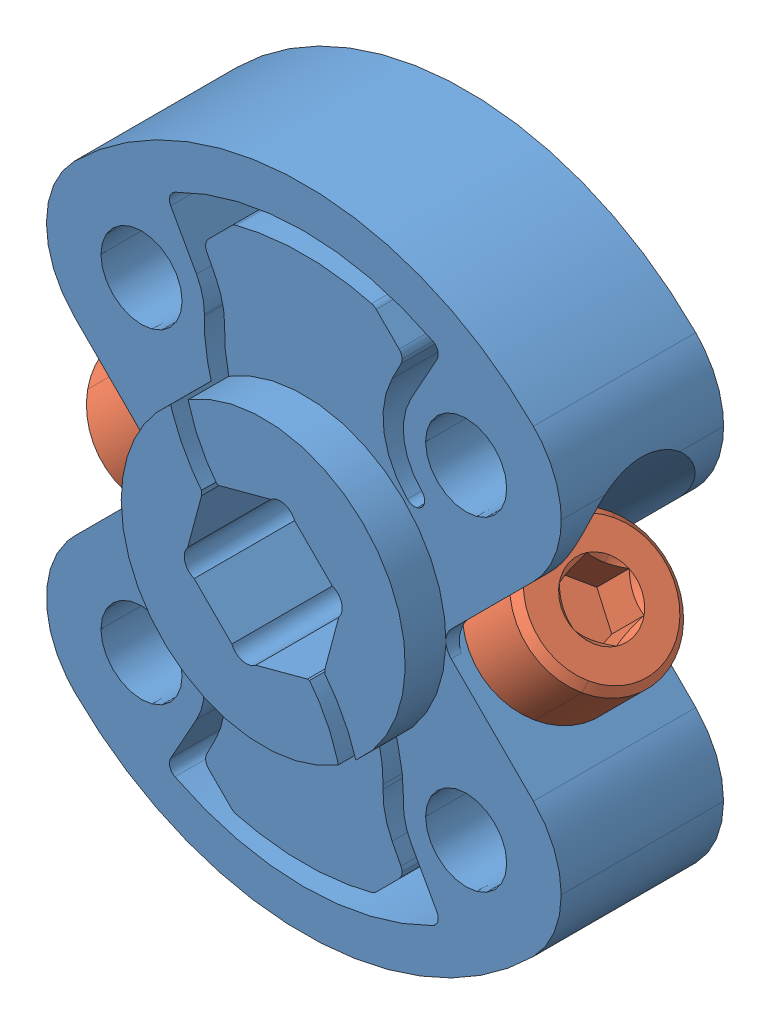
SolidWorks assembly 8mm REX Hub, Thru-hole 1311-0016-4008, configuration Default. Lengths in mm.
Overall size (28.36 32 10.95).
3 component instances, 2 part files, 0 mates.
Components (placement in the parent):
- 1311-0016-4008.STEP-1: 1311-0016-4008.STEP [Default] at (-46.6459 19.0262 11.1883) size (25.38 32 10)
- 2800-0004-0014_90128A207.STEP-1: 2800-0004-0014_90128A207.STEP [Default] at (-48.6988 7.9075 11.1883) x (0.5 -0.5 0.707107) z (-0.707107 -0.707107 0) size (7 7 18.01)
- 2800-0004-0014_90128A207.STEP-2: 2800-0004-0014_90128A207.STEP [Default] at (-44.5931 30.1449 11.1883) x (-0.5 0.5 0.707107) z (0.707107 0.707107 0) size (7 7 18.01)
